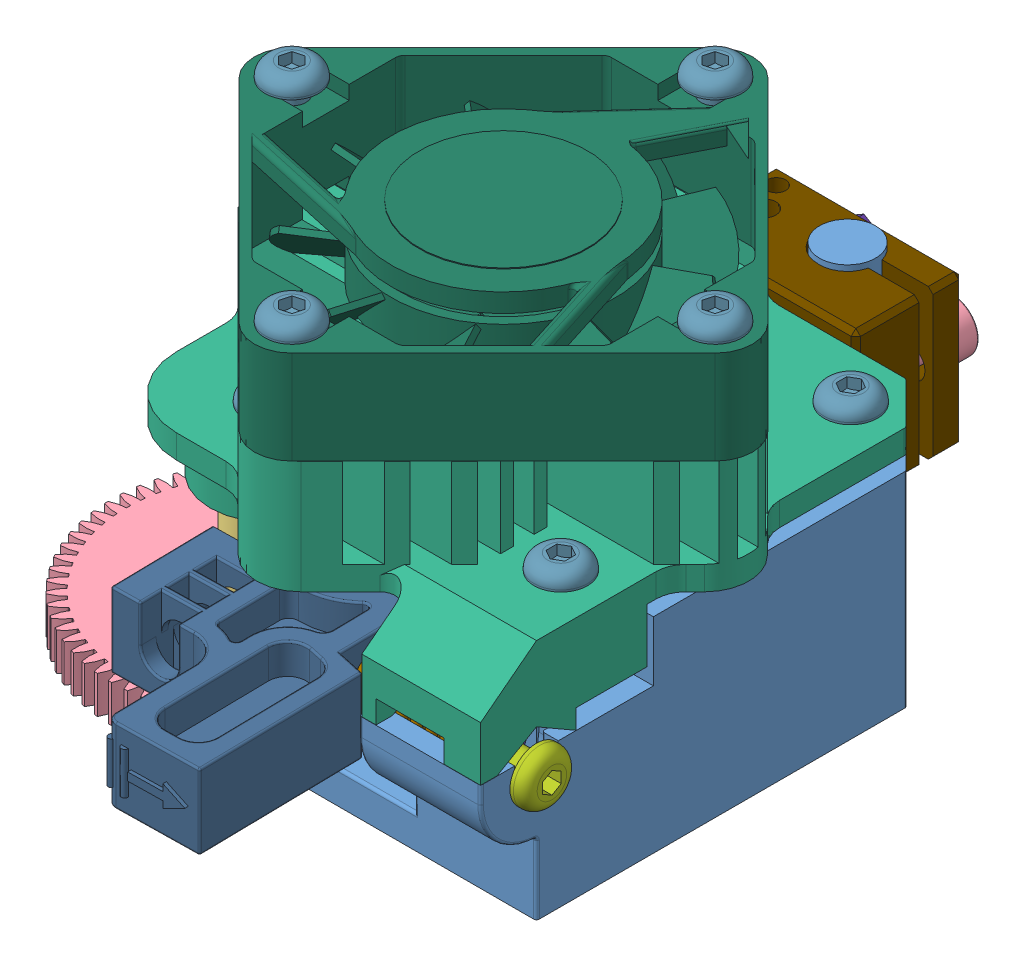
SolidWorks assembly e3d titan areo 1.751, configuration Predeterminado. Lengths in mm.
Overall size (64.29 54.44 90.47).
31 component instances, 23 part files, 0 mates.
Components (placement in the parent):
- Base-1: Base [Predeterminado] at origin size (46 23.41 49.98)
- 9x5x3mm bearing-1: 9x5x3mm bearing [Predeterminado] at (-15.5 4 15.5) x (1 0 0) z (0 -1 0) size (9 9 3)
- hobbed wheel-1: hobbed wheel [Predeterminado] at (-15.5 1.6 15.5) x (-0.447437 0 0.894315) z (0 1 0) size (8.6 8.58 20.6)
- filament gear-1: filament gear [Predeterminado] at (-15.5 8.55 15.5) x (-0.894315 0 -0.447437) z (0 -1 0) size (34 34 4)
- motor gear-1: motor gear [Predeterminado] at (0 8.5 0) x (-0.681998 0 -0.731354) z (0 -1 0) size (11.99 11.99 9)
- cover-1: cover [Predeterminado] at (0 24.9 0) x (1 0 0) z (0 0 -1) size (52.63 28.17 55.14)
- 9x5x3mm bearing-2: 9x5x3mm bearing [Predeterminado] at (-15.5 22.8 15.5) x (1 0 0) z (0 -1 0) size (9 9 3)
- m3x8-1: m3x8 [Predeterminado] at (20.7 13.6 23.3) x (0 0 1) z (0 1 0) size (5.69 9.65 5.69)
- M3 nut-1: M3 nut [Predeterminado] at (16.7 13.6 23.3) x (0 1 0) z (0 0 1) size (6.19 2.71 6.57)
- idler spring-1: idler spring [Predeterminado] at (14.287 13.6 23.3) x (0 0 1) z (-1 0 0) size (6.43 6.45 12.02)
- tensioner-1: tensioner [Predeterminado] at (0 13.6 0) x (0 -1 0) z (0.017452 0 0.999848) size (8.2 21.54 50.88)
- idler bearing pin-1: idler bearing pin [Predeterminado] at (-5.2287 9.6 15.5936) x (0.999848 0 -0.017452) z (0 1 0) size (3.04 3.15 9)
- idler bearing-1: idler bearing [Predeterminado] at (-5.2287 13.6 15.5936) x (0.999848 0 -0.017452) z (0 1 0) size (10 10 4)
- guide tube-1: guide tube [Predeterminado] at (-10.9 13.6 -7.9) x (-1 0 0) z (0 0 1) size (10.9 16.1 22.25)
- ISO 7380 - M3 x 28 v1-1: ISO 7380 - M3 x 28 v1 [Predeterminado] at (-15.5 25.94 15.5) x (0 -1 0) z (0 0 1) size (14.65 5.7 5.7)
- ISO 7380 - M3 x 28 v1-2: ISO 7380 - M3 x 28 v1 [Predeterminado] at (15.5 25.94 15.5) x (0 -1 0) z (0 0 1) size (14.65 5.7 5.7)
- ISO 7380 - M3 x 28 v1-3: ISO 7380 - M3 x 28 v1 [Predeterminado] at (15.5 25.94 -15.5) x (0 -1 0) z (0 0 1) size (14.65 5.7 5.7)
- ISO 7380 - M3 x 28 v1-4: ISO 7380 - M3 x 28 v1 [Predeterminado] at (-21.7 25.94 -14.7) x (0 -1 0) z (0 0 -1) size (14.65 5.7 5.7)
- Fan 40 X 40 X 10 v4-1: Fan 40 X 40 X 10 v4 [Predeterminado] at (-2.3 40.465 3.8274) x (0.707107 0 0.707107) z (-0.707107 0 0.707107) size (40 10.59 40)
- E3D v6 HotEnd - Heatbreak-1: E3D v6 HotEnd - Heatbreak [Predeterminado] at (-10.9 13.6 -31.7812) x (0 1 0) z (0 0 -1) size (7 7 21.9)
- E3D v6 HotEnd - Nozzle-1: E3D v6 HotEnd - Nozzle [Predeterminado] at (-10.4145 12.7757 -42.8188) x (0 1 0) z (0 0 -1) size (8.08 7 12.5)
- E3D v6 HotEnd - Heat Block-1: E3D v6 HotEnd - Heat Block [Predeterminado] at (4.7289 21.3165 -38.3127) x (-1 0 0) z (0 1 0) size (20 11.5 16)
- Ceramic Cartridge Heater-1: Ceramic Cartridge Heater [Predeterminado] at (-3.5983 1.9238 -34.2531) x (0 0 1) z (0 -1 0) size (6 18 29.25)
- Thermistor-1: Thermistor [Predeterminado] at (-7 16.1 -36.0312) x (0 -0.5 0.866025) z (-1 0 0) size (1.5 1.5 7.6)
- HEXAGON SOCKET HEAD CAP SCREWS_SCB3-4-1: HEXAGON SOCKET HEAD CAP SCREWS_SCB3-4 [Predeterminado] at (-2.4 14.6 -33.2312) x (0 1 0) z (1 0 0) size (5.5 5.5 7)
- HEXAGON SOCKET HEAD CAP SCREWS_SCB3-10-1: HEXAGON SOCKET HEAD CAP SCREWS_SCB3-10 [Predeterminado] at (1.5308 13.8272 -37.4189) x (0 1 0) z (0 0 -1) size (5.5 5.5 13)
- Flat Washers_PWF3-1: Flat Washers_PWF3 [Predeterminado] at (-2.4 14.6 -33.2312) x (0 1 0) z (1 0 0) size (6 6 0.5)
- ISO 7380 - M3 x 28 v1-5: ISO 7380 - M3 x 28 v1 [Predeterminado] at (-2.3 45.465 26.4548) x (0 -1 0) z (0.707107 0 0.707107) size (14.65 5.7 5.7)
- ISO 7380 - M3 x 28 v1-6: ISO 7380 - M3 x 28 v1 [Predeterminado] at (-24.9274 45.465 3.8274) x (0 -1 0) z (0.707107 0 0.707107) size (14.65 5.7 5.7)
- ISO 7380 - M3 x 28 v1-7: ISO 7380 - M3 x 28 v1 [Predeterminado] at (-2.3 45.465 -18.8) x (0 -1 0) z (0.707107 0 0.707107) size (14.65 5.7 5.7)
- ISO 7380 - M3 x 28 v1-8: ISO 7380 - M3 x 28 v1 [Predeterminado] at (20.3274 45.465 3.8274) x (0 -1 0) z (0.707107 0 0.707107) size (14.65 5.7 5.7)
